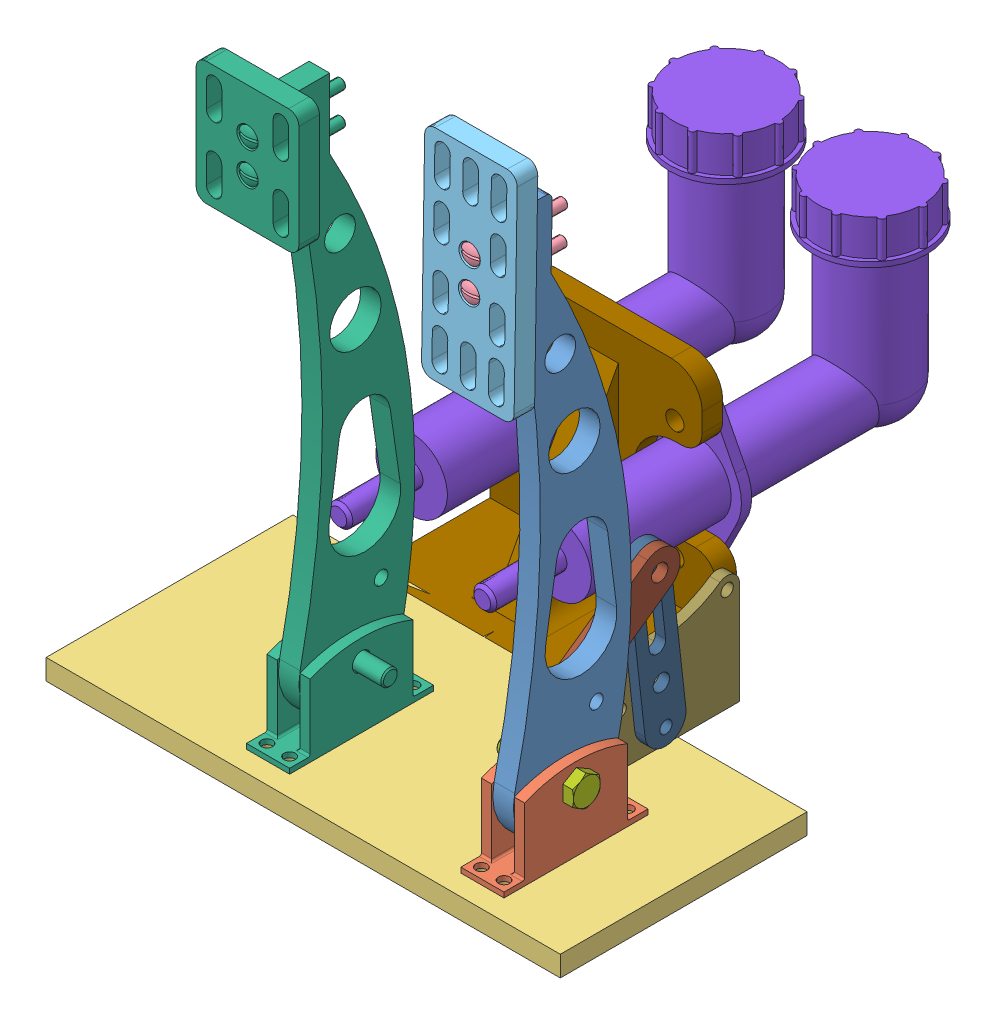
SolidWorks assembly New assembly pedal box SOLIDWORKS IS A DICK, configuration Default. Lengths in mm.
Overall size (367.96 325.08 306.72).
16 component instances, 12 part files, 19 mates.
Components (placement in the parent):
- Pedal Box Final Assembly-1: Pedal Box Final Assembly [Default] at origin size (250 325.08 125.22)
  - Assem1-1: Assem1 [Default] at (125.4355 289.6926 59.207) x (1 0 0) z (0 0.015835 0.999875) size (250 290.71 120.14)
    - Pedal support-1: Pedal support [Default] at (-54.204 -249.8959 -11.4765) x (-1 0 0) z (0 0 -1) size (10 275 71.45)
    - Base Pedal Interface-1: Base Pedal Interface [Default] at (-69.9575 -279.4963 -36.9484) x (1 0 0) z (0 -0.015835 0.999875) size (21 40 70)
    - Base-1: Base [Default] at (-261.3296 -290.6035 32.8844) x (1 0 0) z (0 -0.015835 0.999875) size (250 10 120)
  - din_en_iso2010_m5x45_4_8-1: din_en_iso2010_m5x45_4_8 [Default] at (66.2477 278.3395 93.5761) x (-1 -0.000138 0.000002) z (0 -0.015835 -0.999875) size (9.22 9.3 46.18)
  - din_en_iso2010_m5x45_4_8-2: din_en_iso2010_m5x45_4_8 [Default] at (66.2477 262.3415 93.8294) x (-1 0.000968 -0.000015) z (0 -0.015835 -0.999875) size (9.22 9.3 46.18)
  - Accellerator Pedal-1: Accellerator Pedal [Default] at (43.7477 217.6783 83.8739) x (1 0 0) z (0 0.015835 0.999875) size (45 105 10)
  - Brake pedal assembly-1: Brake pedal assembly [Default] at (-51.1948 166.1795 67.452) x (-1 0 0) z (0 0 -1) size (50 290 82.09)
  - din_en_24017_m8x35-1: din_en_24017_m8x35 [Default] at (76.7315 39.6463 51.689) x (0 0 1) z (-1 0 0) size (13 15.01 40.3)
- CYLINDER-1: CYLINDER [Default] at (-5.3129 58.4863 -88.4163) size (297.96 122.95 224.58)
- CYLINDER-2: CYLINDER [Default] at (-75.3129 58.4863 -88.4163) size (297.96 122.95 224.58)
- Brake c. holder-1: Brake c. holder [Default] at (24.6871 -0.3537 -88.4163) x (-1 0 0) z (0 0 -1) size (109.8 112.89 70)
- link1-1: link1 [Default] at (51.2315 58.5397 -8.4102) x (1 0 0) z (0 0.993729 0.111817) size (5 20 90)
- link2-1: link2 [Default] at (56.2315 78.8629 15.8992) x (1 0 0) z (0 -0.578291 0.815831) size (5 20 70)
- throttle link holder-1: throttle link holder [Default] at (51.2315 59.6463 -13.311) x (-1 0 0) z (0 0 -1) size (25 56 80)
Mates (geometry in assembly coordinates):
- Coincident1: coincident: plane of Pedal Box Final Assembly-1/Assem1-1/Base-1 through (-135.894 9.6463 96.689) normal (0 1 0); line of Brake c. holder-1 through (-95.2129 9.6463 -18.4163) axis (1 0 0)
- Coincident4: coincident: plane of CYLINDER-2 through (-75.3129 58.4863 -88.4163) normal (0 0 1); moEndPointRef_w of Brake c. holder-1
- Concentric1: concentric aligned: cylinder of CYLINDER-2 through (-75.3129 58.4863 -20.4163) axis (0 0 -1) radius 17.4; cylinder of Brake c. holder-1 through (-75.3129 58.4863 -78.4163) axis (0 0 -1) radius 19.9
- Concentric2: concentric aligned: cylinder of CYLINDER-1 through (-5.3129 58.4863 -20.4163) axis (0 0 -1) radius 17.4; cylinder of Brake c. holder-1 through (-5.3129 58.4863 -78.4163) axis (0 0 -1) radius 19.9
- Parallel2: parallel anti-aligned: plane of Pedal Box Final Assembly-1/Assem1-1/Base-1 through (-135.894 9.6463 96.689) normal (0 1 0); plane of Brake c. holder-1 through (-37.3428 -0.3537 -78.4163) normal (0 -1 0)
- Concentric4: concentric anti-aligned: cylinder of CYLINDER-1 through (-5.3129 58.4863 -178.0363) axis (0 0 1) radius 16; cylinder of Brake c. holder-1 through (-5.3129 58.4863 -78.4163) axis (0 0 -1) radius 19.9
- Coincident7: coincident anti-aligned: plane of CYLINDER-1 through (-5.3129 58.4863 -88.4163) normal (0 0 1); plane of Brake c. holder-1 through (4.5871 28.5863 -88.4163) normal (0 0 -1)
- Parallel4: parallel aligned: line of Pedal Box Final Assembly-1/Brake pedal assembly-1 through (-48.5196 12.1463 16.689) axis (1 0 0); line of Brake c. holder-1 through (-95.2129 -0.3537 -18.4163) axis (1 0 0)
- Parallel5: parallel anti-aligned: plane of Pedal Box Final Assembly-1/Assem1-1/Base-1 through (-135.894 9.6463 96.689) normal (0 1 0); plane of Brake c. holder-1 through (-37.3428 -0.3537 -78.4163) normal (0 -1 0)
- Parallel6: parallel aligned: plane of Pedal Box Final Assembly-1/Assem1-1/Base-1 through (-135.894 9.6463 96.689) normal (0 1 0); plane of CYLINDER-2 through (-88.0629 143.3863 -173.3917) normal (0 1 0)
- Parallel7: parallel aligned: plane of Pedal Box Final Assembly-1/Assem1-1/Base-1 through (-135.894 9.6463 96.689) normal (0 1 0); plane of CYLINDER-1 through (-18.0629 143.3863 -173.3917) normal (0 1 0)
- Coincident17: coincident anti-aligned: plane of Pedal Box Final Assembly-1/Assem1-1/Base Pedal Interface-1 through (55.478 9.6463 26.689) normal (0 0 -1); plane of throttle link holder-1 through (46.2315 109.6463 26.689) normal (0 0 1)
- Coincident18: coincident anti-aligned: plane of Pedal Box Final Assembly-1/Assem1-1/Base-1 through (-135.894 9.6463 96.689) normal (0 1 0); plane of throttle link holder-1 through (46.2315 9.6463 -53.311) normal (0 -1 0)
- Coincident26: coincident anti-aligned: plane of link1-1 through (51.2315 93.3202 -4.4966) normal (-1 0 0); plane of throttle link holder-1 through (51.2315 59.6463 -13.311) normal (1 0 0)
- Coincident27: coincident anti-aligned: circle of link1-1; cylinder of throttle link holder-1 through (51.2315 41.6463 -10.311) axis (-1 0 0) radius 4
- Concentric8: concentric anti-aligned: circle of Pedal Box Final Assembly-1/Assem1-1/Pedal support-1; cylinder of link2-1 through (56.2315 64.4057 36.295) axis (1 0 0) radius 4
- Coincident29: coincident anti-aligned: plane of Pedal Box Final Assembly-1/Assem1-1/Pedal support-1 through (61.2315 146.429 22.0236) normal (-1 0 0); plane of link2-1 through (61.2315 64.4057 36.295) normal (1 0 0)
- Coincident30: coincident anti-aligned: plane of link1-1 through (56.2315 93.3202 -4.4966) normal (1 0 0); plane of link2-1 through (56.2315 64.4057 36.295) normal (-1 0 0)
- Coincident31: coincident aligned: circle of link1-1; cylinder of link2-1 through (56.2315 93.3202 -4.4966) axis (1 0 0) radius 4
